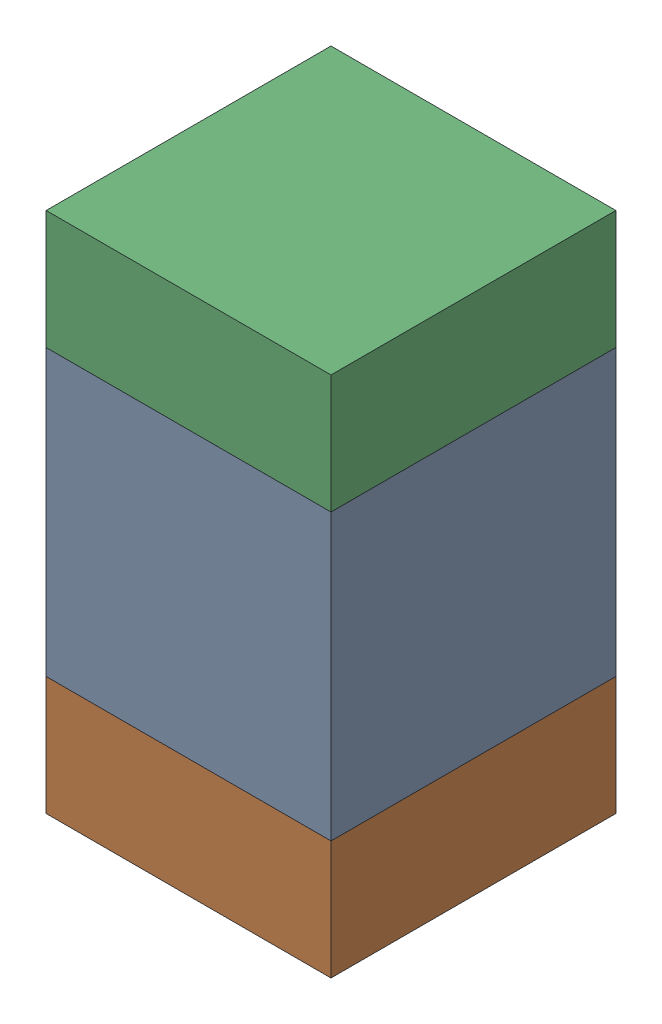
SolidWorks assembly C121_2PCB, configuration Default. Lengths in mm.
Overall size (0.6 1.1 0.6).
6 component instances, 2 part files, 0 mates.
Components (placement in the parent):
- 761606048-1: 761606048 [Default] at (114.2 99.6 0) size (0.6 0.6 0.6)
  - Extruded_9-1: Extruded_9 [Default] at origin size (0.6 0.6 0.6)
- 854785296-1: 854785296 [Default] at (114.2 99.175 0) size (0.6 0.25 0.6)
  - Extruded_10-1: Extruded_10 [Default] at origin size (0.6 0.25 0.6)
- 854785296-2: 854785296 [Default] at (114.2 100.025 0) size (0.6 0.25 0.6)
  - Extruded_10-1: Extruded_10 [Default] at origin size (0.6 0.25 0.6)
